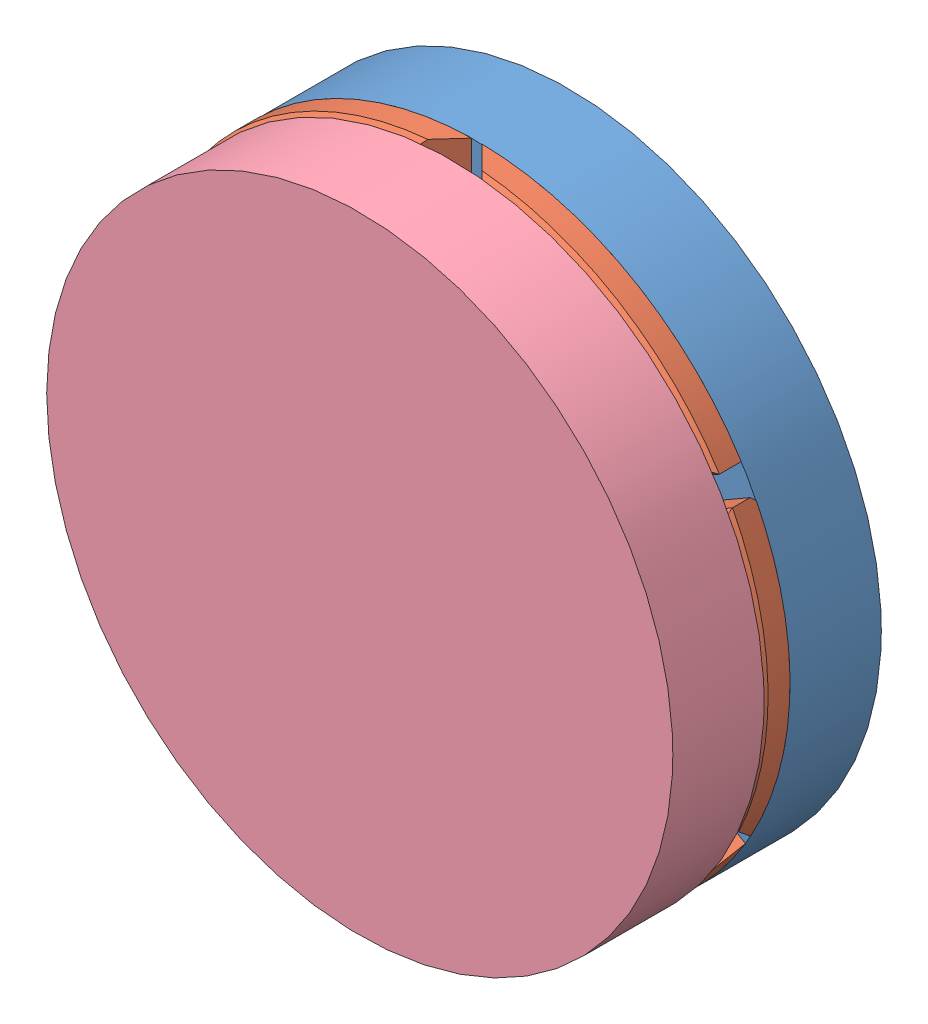
SolidWorks assembly KC_electrical_2, configuration Default. Lengths in mm.
Overall size (76.23 76.56 25.4).
7 component instances, 5 part files, 4 mates.
Components (placement in the parent):
- Part1^KC_electrical_2-1: Part1^KC_electrical_2 [Default] at (70.2815 -23.276 43.4387) size (76.2 76.2 11.11) (virtual)
- Part2^KC_electrical_2-1: Part2^KC_electrical_2 [Default] at (70.2815 -23.276 54.5512) size (76.2 76.16 3.17) (virtual)
- Part3^KC_electrical_2-1: Part3^KC_electrical_2 [Default] at (64.3934 -29.1874 22.1027) size (6.35 6.35 1.59) (virtual)
- Part4^KC_electrical_2-1: Part4^KC_electrical_2 [Default] at (70.3065 -23.6363 -264.9222) size (76.2 76.2 11.11) (virtual)
- Part5^KC_electrical_2-1: Part5^KC_electrical_2 [Default] at (177.8431 -0.9064 -0.6128) size (6.35 6.35 6.35) (virtual)
- Part5^KC_electrical_2-2: Part5^KC_electrical_2 [Default] at (36.223 -128.1307 -0.6128) x (-0.5 -0.866025 0) z (0 0 1) size (6.35 6.35 6.35) (virtual)
- Part5^KC_electrical_2-3: Part5^KC_electrical_2 [Default] at (-3.1464 58.1281 -0.6128) x (-0.5 0.866025 0) z (0 0 1) size (6.35 6.35 6.35) (virtual)
Mates (geometry in assembly coordinates):
- Coincident1: coincident anti-aligned: plane of Part1^KC_electrical_2-1 through (70.2815 -23.276 54.5512) normal (0 0 1); plane of Part2^KC_electrical_2-1 through (70.2815 -23.276 54.5512) normal (0 0 -1)
- Concentric1: concentric anti-aligned: circle of Part1^KC_electrical_2-1; circle of Part3^KC_electrical_2-1
- Coincident4: coincident aligned: circle of Part2^KC_electrical_2-1; circle of Part1^KC_electrical_2-1
- Coincident5: coincident: circle of Part4^KC_electrical_2-1; sphere of Part5^KC_electrical_2-1
